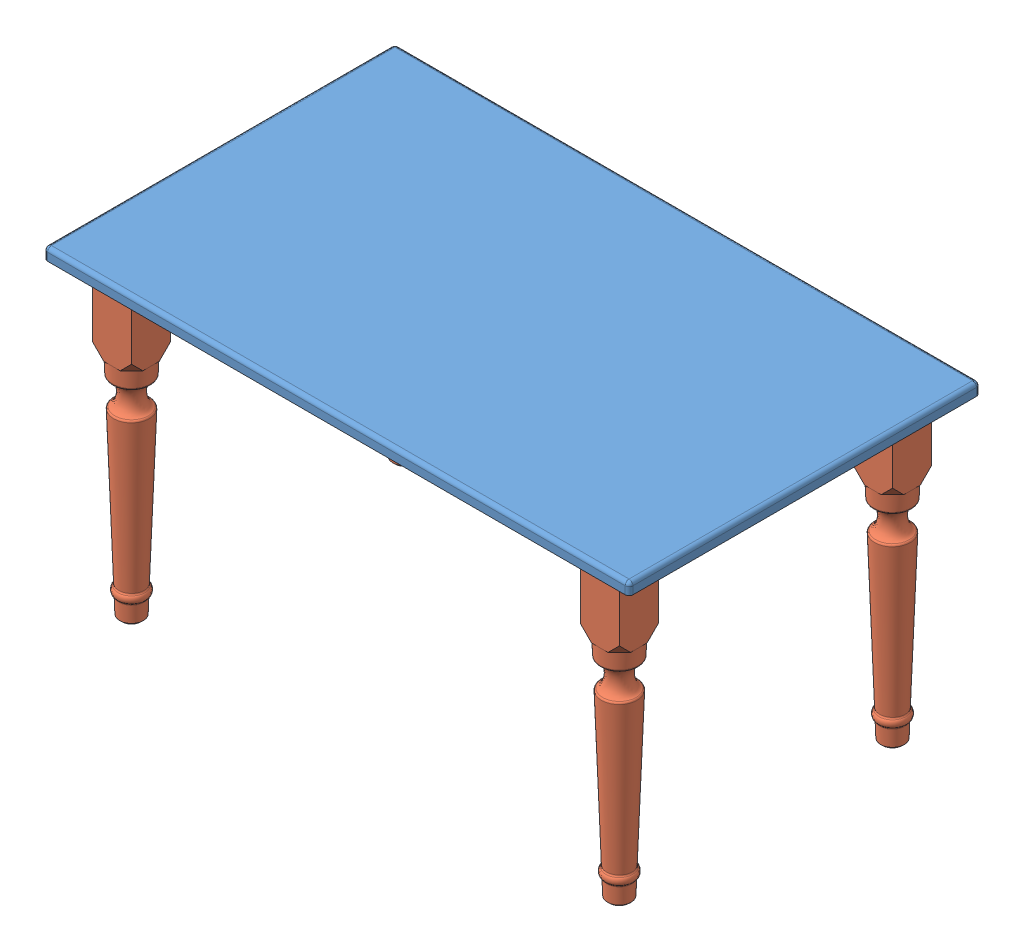
SolidWorks assembly Assemblage1, configuration Défaut. Lengths in mm.
Overall size (1500 810 900).
5 component instances, 2 part files, 12 mates.
Components (placement in the parent):
- C-plan de table-1: C-plan de table [Défaut] at (-790.7409 -24.1898 450) size (1500 30 900)
- C - pied-1: C - pied [Défaut] at (-665.7409 -804.1898 -350) size (100 795 100)
- C - pied-2: C - pied [Défaut] at (-665.7409 -804.1898 350) size (100 795 100)
- C - pied-3: C - pied [Défaut] at (584.2591 -804.1898 350) size (100 795 100)
- C - pied-4: C - pied [Défaut] at (584.2591 -804.1898 -350) size (100 795 100)
Mates (geometry in assembly coordinates):
- Coaxiale1: concentric: cylinder of C-plan de table-1 through (-690.7409 -9.1898 -350) axis (0 -1 0) radius 10; cylinder of C - pied-1 through (-690.7409 -9.1898 -350) axis (0 -1 0) radius 10
- Coïncidente1: coincident: plane of C-plan de table-1 through (-690.7409 -9.1898 -360) normal (0 0 1); plane of C - pied-1 through (-690.7409 -9.1898 -360) normal (0 0 -1)
- Coïncidente2: coincident anti-aligned: plane of C-plan de table-1 through (-790.7409 -24.1898 450) normal (0 -1 0); plane of C - pied-1 through (-665.7409 -24.1898 -350) normal (0 1 0)
- Coaxiale2: concentric: cylinder of C-plan de table-1 through (-690.7409 -9.1898 350) axis (0 -1 0) radius 10; cylinder of C - pied-2 through (-690.7409 -9.1898 350) axis (0 -1 0) radius 10
- Coïncidente3: coincident: plane of C-plan de table-1 through (-690.7409 -9.1898 360) normal (0 0 -1); plane of C - pied-2 through (-690.7409 -9.1898 360) normal (0 0 1)
- Coïncidente4: coincident anti-aligned: plane of C-plan de table-1 through (-790.7409 -24.1898 450) normal (0 -1 0); plane of C - pied-2 through (-665.7409 -24.1898 350) normal (0 1 0)
- Coaxiale3: concentric: cylinder of C-plan de table-1 through (609.2591 -9.1898 350) axis (0 -1 0) radius 10; cylinder of C - pied-3 through (609.2591 -9.1898 350) axis (0 -1 0) radius 10
- Coïncidente5: coincident: plane of C-plan de table-1 through (609.2591 -9.1898 360) normal (0 0 -1); plane of C - pied-3 through (559.2591 -9.1898 360) normal (0 0 1)
- Coïncidente6: coincident anti-aligned: plane of C-plan de table-1 through (-790.7409 -24.1898 450) normal (0 -1 0); plane of C - pied-3 through (584.2591 -24.1898 350) normal (0 1 0)
- Coaxiale4: concentric: cylinder of C-plan de table-1 through (559.2591 -9.1898 -350) axis (0 -1 0) radius 10; cylinder of C - pied-4 through (559.2591 -9.1898 -350) axis (0 -1 0) radius 10
- Coïncidente7: coincident: plane of C-plan de table-1 through (609.2591 -9.1898 -340) normal (0 0 -1); plane of C - pied-4 through (559.2591 -9.1898 -340) normal (0 0 1)
- Coïncidente8: coincident anti-aligned: plane of C-plan de table-1 through (-790.7409 -24.1898 450) normal (0 -1 0); plane of C - pied-4 through (584.2591 -24.1898 -350) normal (0 1 0)
